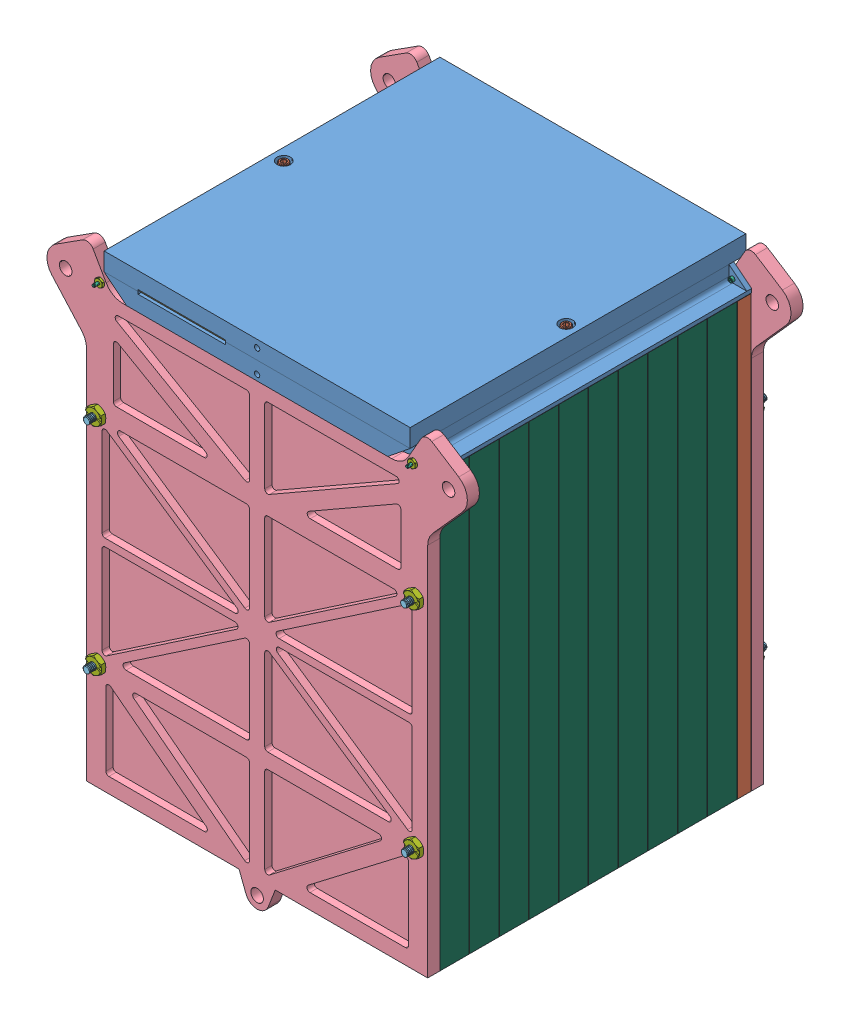
SolidWorks assembly Odd Stack, configuration Default. Lengths in mm.
Overall size (221.56 260.06 190.32).
276 component instances, 25 part files, 68 mates.
Components (placement in the parent):
- Tab Cover Odd-1: Tab Cover Odd [Default] at (178.2276 374.9734 440.7795) x (-1 0 0) z (0 -1 0) size (180.05 176.89 19.05)
- Socket 4-40 0.625in-1: Socket 4-40 0.625in [91251A112] at (252.6326 365.6234 440.7795) x (1 0 0) z (0 -1 0) size (4.65 4.65 19.13)
- Socket 4-40 0.625in-2: Socket 4-40 0.625in [91251A112] at (103.8226 365.6234 440.7795) x (1 0 0) z (0 -1 0) size (4.65 4.65 19.13)
- Steel Hex 4-40 Grade 2-1: Steel Hex 4-40 Grade 2 [90480A005] at (252.6326 367.2577 440.7795) size (6.35 2.87 7.33)
- Steel Hex 4-40 Grade 2-2: Steel Hex 4-40 Grade 2 [90480A005] at (103.8226 367.2577 440.7795) size (6.35 2.87 7.33)
- Two Cell Module-1: Two Cell Module [Default] at (101.24 129.6114 180.5218) size (179.74 245.1 23.68)
  - Cell Tab Config A-1: Cell Tab Config A [Default<As Machined>] at (76.9877 122.2307 189.17) size (160.6 237.16 14.27)
  - Cell Tab Config B-1: Cell Tab Config B [Default<As Machined>] at (76.9877 122.2307 197.4606) x (-1 0 0) z (0 0 -1) size (160.6 237.16 14.66)
  - Tab Load Spreader-1: Tab Load Spreader [Default] at (116.6877 245.8907 191.0069) x (-1 0 0) z (0 1 0) size (56.96 6.41 2.54)
  - Tab Load Spreader-2: Tab Load Spreader [Default] at (37.2877 245.8907 183.3655) x (-1 0 0) z (0 1 0) size (56.96 6.41 2.54)
  - Tab Load Spreader-3: Tab Load Spreader [Default] at (116.6877 242.8507 191.0069) x (-1 0 0) z (0 1 0) size (56.96 6.41 2.54)
  - Tab Load Spreader-4: Tab Load Spreader [Default] at (37.2877 242.8507 183.3655) x (-1 0 0) z (0 1 0) size (56.96 6.41 2.54)
  - Steel Toplock 6-32 Grade 2-1: Steel Toplock 6-32 Grade 2 [91837A008] at (141.9657 242.8507 191.0069) x (1 0 0) z (0 -1 0) size (7.94 9.17 3.14)
  - Steel 6-32 0.4375in-1: Steel 6-32 0.4375in [91251A178] at (141.9657 237.3182 191.0069) x (1 0 0) z (0 -1 0) size (5.74 5.74 15.07)
  - Steel Toplock 6-32 Grade 2-2: Steel Toplock 6-32 Grade 2 [91837A008] at (91.4097 242.8507 191.0069) x (1 0 0) z (0 -1 0) size (7.94 9.17 3.14)
  - Steel Toplock 6-32 Grade 2-3: Steel Toplock 6-32 Grade 2 [91837A008] at (62.5657 242.8507 183.3655) x (1 0 0) z (0 -1 0) size (7.94 9.17 3.14)
  - Steel Toplock 6-32 Grade 2-4: Steel Toplock 6-32 Grade 2 [91837A008] at (12.0097 242.8507 183.3655) x (1 0 0) z (0 -1 0) size (7.94 9.17 3.14)
  - Steel 6-32 0.4375in-2: Steel 6-32 0.4375in [91251A178] at (91.4097 237.3182 191.0069) x (1 0 0) z (0 -1 0) size (5.74 5.74 15.07)
  - Steel 6-32 0.4375in-3: Steel 6-32 0.4375in [91251A178] at (62.5657 237.3182 183.3655) x (1 0 0) z (0 -1 0) size (5.74 5.74 15.07)
  - Steel 6-32 0.4375in-4: Steel 6-32 0.4375in [91251A178] at (12.0097 237.3182 183.3655) x (1 0 0) z (0 -1 0) size (5.74 5.74 15.07)
  - Cell Board Middle-1: Cell Board Middle [Default] at (76.9877 244.9032 188.87) x (-1 0 0) z (0 0 1) size (20.32 17.15 2.64)
  - Cell Board Middle-2: Cell Board Middle [Default] at (76.9877 244.9032 197.1606) size (20.32 17.15 2.64)
  - Repeating Frame Outer-1: Repeating Frame Outer [Default] at (76.9877 115.9807 198.7766) size (179.3 226.63 1.59)
  - Repeating Frame Outer-2: Repeating Frame Outer [Default] at (76.9877 115.9807 186.2665) size (179.3 226.63 1.59)
  - Repeating Frame Inner-1: Repeating Frame Inner [Default] at (76.9877 116.0307 190.8106) size (179.3 226.73 6.35)
  - Insulation Film Back-1: Insulation Film Back [Default] at (76.9877 122.0246 185.62) x (-1 0 0) z (0 0 -1) size (179.74 227.29 0.36)
  - Insulation Film Full-1: Insulation Film Full [Default] at (76.9876 122.0664 201.0792) x (-1 0 0) z (0 0 -1) size (179.74 227.22 15.52)
  - Cell Load Spreader-1: Cell Load Spreader [Default] at (76.9877 115.9807 192.72) size (154 205.5 1.19)
  - Heat Sink Full-1: Heat Sink Full [Default] at (76.9877 122.0321 201.2316) x (-1 0 0) z (0 0 -1) size (179.74 227.15 15.45)
- Positive End Module-1: Positive End Module [Default] at (225.9096 129.8563 535.5842) x (-1 0 0) z (0 0 -1) size (179.74 245.1 14.97)
  - Cell Tab Config B Positive End-1: Cell Tab Config B Positive End [Default<As Machined>] at (47.682 121.9858 173.2819) size (160.6 236.86 14.97)
  - Repeating Frame Outer-1: Repeating Frame Outer [Default] at (47.682 115.7358 173.5819) size (179.3 226.63 1.59)
  - Repeating Frame Outer-2: Repeating Frame Outer [Default] at (47.682 115.7358 175.1694) size (179.3 226.63 1.59)
  - Repeating Frame Outer-3: Repeating Frame Outer [Default] at (47.682 115.7358 170.3784) size (179.3 226.63 1.59)
  - Cell Board End-1: Cell Board End [Default] at (47.682 240.5308 169.1719) x (-1 0 0) z (0 0 1) size (20.32 25.4 3.91)
  - Insulation Film Half-1: Insulation Film Half [Default] at (47.682 121.8215 169.6633) size (179.74 227.22 7.27)
  - Insulation Film End-1: Insulation Film End [Default] at (47.682 115.7358 176.8319) size (154 205.5 0.07)
  - Heat Sink Half-1: Heat Sink Half [Default] at (47.682 121.7872 169.5109) size (179.74 227.15 7.2)
- Negative End Module Odd-1: Negative End Module Odd [Default] at (101.24 129.6115 321.6437) size (179.74 245.1 28.8)
  - Cell Tab Config A-1: Cell Tab Config A [Default<As Machined>] at (76.9877 122.2307 189.17) size (160.6 237.16 14.27)
  - Cell Tab Config B Negative End-1: Cell Tab Config B Negative End [Default<As Machined>] at (76.9877 122.2307 197.4606) x (-1 0 0) z (0 0 -1) size (160.6 237.16 19.78)
  - Tab Load Spreader-1: Tab Load Spreader [Default] at (116.6877 245.8907 191.0069) x (-1 0 0) z (0 1 0) size (56.96 6.41 2.54)
  - Tab Load Spreader-2: Tab Load Spreader [Default] at (37.2877 245.8907 183.3655) x (-1 0 0) z (0 1 0) size (56.96 6.41 2.54)
  - Tab Load Spreader-3: Tab Load Spreader [Default] at (116.6877 242.8507 191.0069) x (-1 0 0) z (0 1 0) size (56.96 6.41 2.54)
  - Tab Load Spreader-4: Tab Load Spreader [Default] at (37.2877 242.8507 183.3655) x (-1 0 0) z (0 1 0) size (56.96 6.41 2.54)
  - Steel Toplock 6-32 Grade 2-1: Steel Toplock 6-32 Grade 2 [91837A008] at (141.9657 242.8507 191.0069) x (1 0 0) z (0 -1 0) size (7.94 9.17 3.14)
  - Steel Toplock 6-32 Grade 2-2: Steel Toplock 6-32 Grade 2 [91837A008] at (91.4097 242.8507 191.0069) x (1 0 0) z (0 -1 0) size (7.94 9.17 3.14)
  - Steel Toplock 6-32 Grade 2-3: Steel Toplock 6-32 Grade 2 [91837A008] at (62.5657 242.8507 183.3655) x (1 0 0) z (0 -1 0) size (7.94 9.17 3.14)
  - Steel Toplock 6-32 Grade 2-4: Steel Toplock 6-32 Grade 2 [91837A008] at (12.0097 242.8507 183.3655) x (1 0 0) z (0 -1 0) size (7.94 9.17 3.14)
  - Steel 6-32 0.4375in-1: Steel 6-32 0.4375in [91251A178] at (141.9657 237.3182 191.0069) x (1 0 0) z (0 -1 0) size (5.74 5.74 15.07)
  - Steel 6-32 0.4375in-2: Steel 6-32 0.4375in [91251A178] at (91.4097 237.3182 191.0069) x (1 0 0) z (0 -1 0) size (5.74 5.74 15.07)
  - Steel 6-32 0.4375in-3: Steel 6-32 0.4375in [91251A178] at (62.5657 237.3182 183.3655) x (1 0 0) z (0 -1 0) size (5.74 5.74 15.07)
  - Steel 6-32 0.4375in-4: Steel 6-32 0.4375in [91251A178] at (12.0097 237.3182 183.3655) x (1 0 0) z (0 -1 0) size (5.74 5.74 15.07)
  - Repeating Frame Outer-1: Repeating Frame Outer [Default] at (76.9877 115.9807 186.2665) size (179.3 226.63 1.59)
  - Repeating Frame Inner-1: Repeating Frame Inner [Default] at (76.9877 116.0307 190.8106) size (179.3 226.73 6.35)
  - Repeating Frame Outer-2: Repeating Frame Outer [Default] at (76.9877 115.9807 198.7766) size (179.3 226.63 1.59)
  - Cell Board Middle-1: Cell Board Middle [Default] at (76.9877 244.9032 188.87) x (-1 0 0) z (0 0 1) size (20.32 17.15 2.64)
  - Cell Board End-1: Cell Board End [Default] at (76.9877 240.7757 197.1606) x (1 0 0) z (0 0 -1) size (20.32 25.4 3.91)
  - Insulation Film Back-1: Insulation Film Back [Default] at (76.9877 122.0245 185.62) x (-1 0 0) z (0 0 -1) size (179.74 227.29 0.36)
  - Insulation Film Full-1: Insulation Film Full [Default] at (76.9876 122.0664 201.0792) x (-1 0 0) z (0 0 -1) size (179.74 227.22 15.52)
  - Cell Load Spreader-1: Cell Load Spreader [Default] at (76.9877 115.9807 192.72) size (154 205.5 1.19)
  - Heat Sink Full-1: Heat Sink Full [Default] at (76.9877 122.0321 201.2316) x (-1 0 0) z (0 0 -1) size (179.74 227.15 15.45)
- Two Cell Module-2: Two Cell Module [Default] at (101.24 129.6114 196.202) size (179.74 245.1 23.68)
  - Cell Tab Config A-1: Cell Tab Config A [Default<As Machined>] at (76.9877 122.2307 189.17) size (160.6 237.16 14.27)
  - Cell Tab Config B-1: Cell Tab Config B [Default<As Machined>] at (76.9877 122.2307 197.4606) x (-1 0 0) z (0 0 -1) size (160.6 237.16 14.66)
  - Tab Load Spreader-1: Tab Load Spreader [Default] at (116.6877 245.8907 191.0069) x (-1 0 0) z (0 1 0) size (56.96 6.41 2.54)
  - Tab Load Spreader-2: Tab Load Spreader [Default] at (37.2877 245.8907 183.3655) x (-1 0 0) z (0 1 0) size (56.96 6.41 2.54)
  - Tab Load Spreader-3: Tab Load Spreader [Default] at (116.6877 242.8507 191.0069) x (-1 0 0) z (0 1 0) size (56.96 6.41 2.54)
  - Tab Load Spreader-4: Tab Load Spreader [Default] at (37.2877 242.8507 183.3655) x (-1 0 0) z (0 1 0) size (56.96 6.41 2.54)
  - Steel Toplock 6-32 Grade 2-1: Steel Toplock 6-32 Grade 2 [91837A008] at (141.9657 242.8507 191.0069) x (1 0 0) z (0 -1 0) size (7.94 9.17 3.14)
  - Steel 6-32 0.4375in-1: Steel 6-32 0.4375in [91251A178] at (141.9657 237.3182 191.0069) x (1 0 0) z (0 -1 0) size (5.74 5.74 15.07)
  - Steel Toplock 6-32 Grade 2-2: Steel Toplock 6-32 Grade 2 [91837A008] at (91.4097 242.8507 191.0069) x (1 0 0) z (0 -1 0) size (7.94 9.17 3.14)
  - Steel Toplock 6-32 Grade 2-3: Steel Toplock 6-32 Grade 2 [91837A008] at (62.5657 242.8507 183.3655) x (1 0 0) z (0 -1 0) size (7.94 9.17 3.14)
  - Steel Toplock 6-32 Grade 2-4: Steel Toplock 6-32 Grade 2 [91837A008] at (12.0097 242.8507 183.3655) x (1 0 0) z (0 -1 0) size (7.94 9.17 3.14)
  - Steel 6-32 0.4375in-2: Steel 6-32 0.4375in [91251A178] at (91.4097 237.3182 191.0069) x (1 0 0) z (0 -1 0) size (5.74 5.74 15.07)
  - Steel 6-32 0.4375in-3: Steel 6-32 0.4375in [91251A178] at (62.5657 237.3182 183.3655) x (1 0 0) z (0 -1 0) size (5.74 5.74 15.07)
  - Steel 6-32 0.4375in-4: Steel 6-32 0.4375in [91251A178] at (12.0097 237.3182 183.3655) x (1 0 0) z (0 -1 0) size (5.74 5.74 15.07)
  - Cell Board Middle-1: Cell Board Middle [Default] at (76.9877 244.9032 188.87) x (-1 0 0) z (0 0 1) size (20.32 17.15 2.64)
  - Cell Board Middle-2: Cell Board Middle [Default] at (76.9877 244.9032 197.1606) size (20.32 17.15 2.64)
  - Repeating Frame Outer-1: Repeating Frame Outer [Default] at (76.9877 115.9807 198.7766) size (179.3 226.63 1.59)
  - Repeating Frame Outer-2: Repeating Frame Outer [Default] at (76.9877 115.9807 186.2665) size (179.3 226.63 1.59)
  - Repeating Frame Inner-1: Repeating Frame Inner [Default] at (76.9877 116.0307 190.8106) size (179.3 226.73 6.35)
  - Insulation Film Back-1: Insulation Film Back [Default] at (76.9877 122.0246 185.62) x (-1 0 0) z (0 0 -1) size (179.74 227.29 0.36)
  - Insulation Film Full-1: Insulation Film Full [Default] at (76.9876 122.0664 201.0792) x (-1 0 0) z (0 0 -1) size (179.74 227.22 15.52)
  - Cell Load Spreader-1: Cell Load Spreader [Default] at (76.9877 115.9807 192.72) size (154 205.5 1.19)
  - Heat Sink Full-1: Heat Sink Full [Default] at (76.9877 122.0321 201.2316) x (-1 0 0) z (0 0 -1) size (179.74 227.15 15.45)
- Two Cell Module-3: Two Cell Module [Default] at (101.24 129.6114 211.8822) size (179.74 245.1 23.68)
  - Cell Tab Config A-1: Cell Tab Config A [Default<As Machined>] at (76.9877 122.2307 189.17) size (160.6 237.16 14.27)
  - Cell Tab Config B-1: Cell Tab Config B [Default<As Machined>] at (76.9877 122.2307 197.4606) x (-1 0 0) z (0 0 -1) size (160.6 237.16 14.66)
  - Tab Load Spreader-1: Tab Load Spreader [Default] at (116.6877 245.8907 191.0069) x (-1 0 0) z (0 1 0) size (56.96 6.41 2.54)
  - Tab Load Spreader-2: Tab Load Spreader [Default] at (37.2877 245.8907 183.3655) x (-1 0 0) z (0 1 0) size (56.96 6.41 2.54)
  - Tab Load Spreader-3: Tab Load Spreader [Default] at (116.6877 242.8507 191.0069) x (-1 0 0) z (0 1 0) size (56.96 6.41 2.54)
  - Tab Load Spreader-4: Tab Load Spreader [Default] at (37.2877 242.8507 183.3655) x (-1 0 0) z (0 1 0) size (56.96 6.41 2.54)
  - Steel Toplock 6-32 Grade 2-1: Steel Toplock 6-32 Grade 2 [91837A008] at (141.9657 242.8507 191.0069) x (1 0 0) z (0 -1 0) size (7.94 9.17 3.14)
  - Steel 6-32 0.4375in-1: Steel 6-32 0.4375in [91251A178] at (141.9657 237.3182 191.0069) x (1 0 0) z (0 -1 0) size (5.74 5.74 15.07)
  - Steel Toplock 6-32 Grade 2-2: Steel Toplock 6-32 Grade 2 [91837A008] at (91.4097 242.8507 191.0069) x (1 0 0) z (0 -1 0) size (7.94 9.17 3.14)
  - Steel Toplock 6-32 Grade 2-3: Steel Toplock 6-32 Grade 2 [91837A008] at (62.5657 242.8507 183.3655) x (1 0 0) z (0 -1 0) size (7.94 9.17 3.14)
  - Steel Toplock 6-32 Grade 2-4: Steel Toplock 6-32 Grade 2 [91837A008] at (12.0097 242.8507 183.3655) x (1 0 0) z (0 -1 0) size (7.94 9.17 3.14)
  - Steel 6-32 0.4375in-2: Steel 6-32 0.4375in [91251A178] at (91.4097 237.3182 191.0069) x (1 0 0) z (0 -1 0) size (5.74 5.74 15.07)
  - Steel 6-32 0.4375in-3: Steel 6-32 0.4375in [91251A178] at (62.5657 237.3182 183.3655) x (1 0 0) z (0 -1 0) size (5.74 5.74 15.07)
  - Steel 6-32 0.4375in-4: Steel 6-32 0.4375in [91251A178] at (12.0097 237.3182 183.3655) x (1 0 0) z (0 -1 0) size (5.74 5.74 15.07)
  - Cell Board Middle-1: Cell Board Middle [Default] at (76.9877 244.9032 188.87) x (-1 0 0) z (0 0 1) size (20.32 17.15 2.64)
  - Cell Board Middle-2: Cell Board Middle [Default] at (76.9877 244.9032 197.1606) size (20.32 17.15 2.64)
  - Repeating Frame Outer-1: Repeating Frame Outer [Default] at (76.9877 115.9807 198.7766) size (179.3 226.63 1.59)
  - Repeating Frame Outer-2: Repeating Frame Outer [Default] at (76.9877 115.9807 186.2665) size (179.3 226.63 1.59)
  - Repeating Frame Inner-1: Repeating Frame Inner [Default] at (76.9877 116.0307 190.8106) size (179.3 226.73 6.35)
  - Insulation Film Back-1: Insulation Film Back [Default] at (76.9877 122.0246 185.62) x (-1 0 0) z (0 0 -1) size (179.74 227.29 0.36)
  - Insulation Film Full-1: Insulation Film Full [Default] at (76.9876 122.0664 201.0792) x (-1 0 0) z (0 0 -1) size (179.74 227.22 15.52)
  - Cell Load Spreader-1: Cell Load Spreader [Default] at (76.9877 115.9807 192.72) size (154 205.5 1.19)
  - Heat Sink Full-1: Heat Sink Full [Default] at (76.9877 122.0321 201.2316) x (-1 0 0) z (0 0 -1) size (179.74 227.15 15.45)
- Two Cell Module-4: Two Cell Module [Default] at (101.24 129.6114 227.5624) size (179.74 245.1 23.68)
  - Cell Tab Config A-1: Cell Tab Config A [Default<As Machined>] at (76.9877 122.2307 189.17) size (160.6 237.16 14.27)
  - Cell Tab Config B-1: Cell Tab Config B [Default<As Machined>] at (76.9877 122.2307 197.4606) x (-1 0 0) z (0 0 -1) size (160.6 237.16 14.66)
  - Tab Load Spreader-1: Tab Load Spreader [Default] at (116.6877 245.8907 191.0069) x (-1 0 0) z (0 1 0) size (56.96 6.41 2.54)
  - Tab Load Spreader-2: Tab Load Spreader [Default] at (37.2877 245.8907 183.3655) x (-1 0 0) z (0 1 0) size (56.96 6.41 2.54)
  - Tab Load Spreader-3: Tab Load Spreader [Default] at (116.6877 242.8507 191.0069) x (-1 0 0) z (0 1 0) size (56.96 6.41 2.54)
  - Tab Load Spreader-4: Tab Load Spreader [Default] at (37.2877 242.8507 183.3655) x (-1 0 0) z (0 1 0) size (56.96 6.41 2.54)
  - Steel Toplock 6-32 Grade 2-1: Steel Toplock 6-32 Grade 2 [91837A008] at (141.9657 242.8507 191.0069) x (1 0 0) z (0 -1 0) size (7.94 9.17 3.14)
  - Steel 6-32 0.4375in-1: Steel 6-32 0.4375in [91251A178] at (141.9657 237.3182 191.0069) x (1 0 0) z (0 -1 0) size (5.74 5.74 15.07)
  - Steel Toplock 6-32 Grade 2-2: Steel Toplock 6-32 Grade 2 [91837A008] at (91.4097 242.8507 191.0069) x (1 0 0) z (0 -1 0) size (7.94 9.17 3.14)
  - Steel Toplock 6-32 Grade 2-3: Steel Toplock 6-32 Grade 2 [91837A008] at (62.5657 242.8507 183.3655) x (1 0 0) z (0 -1 0) size (7.94 9.17 3.14)
  - Steel Toplock 6-32 Grade 2-4: Steel Toplock 6-32 Grade 2 [91837A008] at (12.0097 242.8507 183.3655) x (1 0 0) z (0 -1 0) size (7.94 9.17 3.14)
  - Steel 6-32 0.4375in-2: Steel 6-32 0.4375in [91251A178] at (91.4097 237.3182 191.0069) x (1 0 0) z (0 -1 0) size (5.74 5.74 15.07)
  - Steel 6-32 0.4375in-3: Steel 6-32 0.4375in [91251A178] at (62.5657 237.3182 183.3655) x (1 0 0) z (0 -1 0) size (5.74 5.74 15.07)
  - Steel 6-32 0.4375in-4: Steel 6-32 0.4375in [91251A178] at (12.0097 237.3182 183.3655) x (1 0 0) z (0 -1 0) size (5.74 5.74 15.07)
  - Cell Board Middle-1: Cell Board Middle [Default] at (76.9877 244.9032 188.87) x (-1 0 0) z (0 0 1) size (20.32 17.15 2.64)
  - Cell Board Middle-2: Cell Board Middle [Default] at (76.9877 244.9032 197.1606) size (20.32 17.15 2.64)
  - Repeating Frame Outer-1: Repeating Frame Outer [Default] at (76.9877 115.9807 198.7766) size (179.3 226.63 1.59)
  - Repeating Frame Outer-2: Repeating Frame Outer [Default] at (76.9877 115.9807 186.2665) size (179.3 226.63 1.59)
  - Repeating Frame Inner-1: Repeating Frame Inner [Default] at (76.9877 116.0307 190.8106) size (179.3 226.73 6.35)
  - Insulation Film Back-1: Insulation Film Back [Default] at (76.9877 122.0246 185.62) x (-1 0 0) z (0 0 -1) size (179.74 227.29 0.36)
  - Insulation Film Full-1: Insulation Film Full [Default] at (76.9876 122.0664 201.0792) x (-1 0 0) z (0 0 -1) size (179.74 227.22 15.52)
  - Cell Load Spreader-1: Cell Load Spreader [Default] at (76.9877 115.9807 192.72) size (154 205.5 1.19)
  - Heat Sink Full-1: Heat Sink Full [Default] at (76.9877 122.0321 201.2316) x (-1 0 0) z (0 0 -1) size (179.74 227.15 15.45)
- Two Cell Module-5: Two Cell Module [Default] at (101.24 129.6114 243.2426) size (179.74 245.1 23.68)
  - Cell Tab Config A-1: Cell Tab Config A [Default<As Machined>] at (76.9877 122.2307 189.17) size (160.6 237.16 14.27)
  - Cell Tab Config B-1: Cell Tab Config B [Default<As Machined>] at (76.9877 122.2307 197.4606) x (-1 0 0) z (0 0 -1) size (160.6 237.16 14.66)
  - Tab Load Spreader-1: Tab Load Spreader [Default] at (116.6877 245.8907 191.0069) x (-1 0 0) z (0 1 0) size (56.96 6.41 2.54)
  - Tab Load Spreader-2: Tab Load Spreader [Default] at (37.2877 245.8907 183.3655) x (-1 0 0) z (0 1 0) size (56.96 6.41 2.54)
  - Tab Load Spreader-3: Tab Load Spreader [Default] at (116.6877 242.8507 191.0069) x (-1 0 0) z (0 1 0) size (56.96 6.41 2.54)
  - Tab Load Spreader-4: Tab Load Spreader [Default] at (37.2877 242.8507 183.3655) x (-1 0 0) z (0 1 0) size (56.96 6.41 2.54)
  - Steel Toplock 6-32 Grade 2-1: Steel Toplock 6-32 Grade 2 [91837A008] at (141.9657 242.8507 191.0069) x (1 0 0) z (0 -1 0) size (7.94 9.17 3.14)
  - Steel 6-32 0.4375in-1: Steel 6-32 0.4375in [91251A178] at (141.9657 237.3182 191.0069) x (1 0 0) z (0 -1 0) size (5.74 5.74 15.07)
  - Steel Toplock 6-32 Grade 2-2: Steel Toplock 6-32 Grade 2 [91837A008] at (91.4097 242.8507 191.0069) x (1 0 0) z (0 -1 0) size (7.94 9.17 3.14)
  - Steel Toplock 6-32 Grade 2-3: Steel Toplock 6-32 Grade 2 [91837A008] at (62.5657 242.8507 183.3655) x (1 0 0) z (0 -1 0) size (7.94 9.17 3.14)
  - Steel Toplock 6-32 Grade 2-4: Steel Toplock 6-32 Grade 2 [91837A008] at (12.0097 242.8507 183.3655) x (1 0 0) z (0 -1 0) size (7.94 9.17 3.14)
  - Steel 6-32 0.4375in-2: Steel 6-32 0.4375in [91251A178] at (91.4097 237.3182 191.0069) x (1 0 0) z (0 -1 0) size (5.74 5.74 15.07)
  - Steel 6-32 0.4375in-3: Steel 6-32 0.4375in [91251A178] at (62.5657 237.3182 183.3655) x (1 0 0) z (0 -1 0) size (5.74 5.74 15.07)
  - Steel 6-32 0.4375in-4: Steel 6-32 0.4375in [91251A178] at (12.0097 237.3182 183.3655) x (1 0 0) z (0 -1 0) size (5.74 5.74 15.07)
  - Cell Board Middle-1: Cell Board Middle [Default] at (76.9877 244.9032 188.87) x (-1 0 0) z (0 0 1) size (20.32 17.15 2.64)
  - Cell Board Middle-2: Cell Board Middle [Default] at (76.9877 244.9032 197.1606) size (20.32 17.15 2.64)
  - Repeating Frame Outer-1: Repeating Frame Outer [Default] at (76.9877 115.9807 198.7766) size (179.3 226.63 1.59)
  - Repeating Frame Outer-2: Repeating Frame Outer [Default] at (76.9877 115.9807 186.2665) size (179.3 226.63 1.59)
  - Repeating Frame Inner-1: Repeating Frame Inner [Default] at (76.9877 116.0307 190.8106) size (179.3 226.73 6.35)
  - Insulation Film Back-1: Insulation Film Back [Default] at (76.9877 122.0246 185.62) x (-1 0 0) z (0 0 -1) size (179.74 227.29 0.36)
  - Insulation Film Full-1: Insulation Film Full [Default] at (76.9876 122.0664 201.0792) x (-1 0 0) z (0 0 -1) size (179.74 227.22 15.52)
  - Cell Load Spreader-1: Cell Load Spreader [Default] at (76.9877 115.9807 192.72) size (154 205.5 1.19)
  - Heat Sink Full-1: Heat Sink Full [Default] at (76.9877 122.0321 201.2316) x (-1 0 0) z (0 0 -1) size (179.74 227.15 15.45)
- Two Cell Module-6: Two Cell Module [Default] at (101.24 129.6114 258.9228) size (179.74 245.1 23.68)
  - Cell Tab Config A-1: Cell Tab Config A [Default<As Machined>] at (76.9877 122.2307 189.17) size (160.6 237.16 14.27)
  - Cell Tab Config B-1: Cell Tab Config B [Default<As Machined>] at (76.9877 122.2307 197.4606) x (-1 0 0) z (0 0 -1) size (160.6 237.16 14.66)
  - Tab Load Spreader-1: Tab Load Spreader [Default] at (116.6877 245.8907 191.0069) x (-1 0 0) z (0 1 0) size (56.96 6.41 2.54)
  - Tab Load Spreader-2: Tab Load Spreader [Default] at (37.2877 245.8907 183.3655) x (-1 0 0) z (0 1 0) size (56.96 6.41 2.54)
  - Tab Load Spreader-3: Tab Load Spreader [Default] at (116.6877 242.8507 191.0069) x (-1 0 0) z (0 1 0) size (56.96 6.41 2.54)
  - Tab Load Spreader-4: Tab Load Spreader [Default] at (37.2877 242.8507 183.3655) x (-1 0 0) z (0 1 0) size (56.96 6.41 2.54)
  - Steel Toplock 6-32 Grade 2-1: Steel Toplock 6-32 Grade 2 [91837A008] at (141.9657 242.8507 191.0069) x (1 0 0) z (0 -1 0) size (7.94 9.17 3.14)
  - Steel 6-32 0.4375in-1: Steel 6-32 0.4375in [91251A178] at (141.9657 237.3182 191.0069) x (1 0 0) z (0 -1 0) size (5.74 5.74 15.07)
  - Steel Toplock 6-32 Grade 2-2: Steel Toplock 6-32 Grade 2 [91837A008] at (91.4097 242.8507 191.0069) x (1 0 0) z (0 -1 0) size (7.94 9.17 3.14)
  - Steel Toplock 6-32 Grade 2-3: Steel Toplock 6-32 Grade 2 [91837A008] at (62.5657 242.8507 183.3655) x (1 0 0) z (0 -1 0) size (7.94 9.17 3.14)
  - Steel Toplock 6-32 Grade 2-4: Steel Toplock 6-32 Grade 2 [91837A008] at (12.0097 242.8507 183.3655) x (1 0 0) z (0 -1 0) size (7.94 9.17 3.14)
  - Steel 6-32 0.4375in-2: Steel 6-32 0.4375in [91251A178] at (91.4097 237.3182 191.0069) x (1 0 0) z (0 -1 0) size (5.74 5.74 15.07)
  - Steel 6-32 0.4375in-3: Steel 6-32 0.4375in [91251A178] at (62.5657 237.3182 183.3655) x (1 0 0) z (0 -1 0) size (5.74 5.74 15.07)
  - Steel 6-32 0.4375in-4: Steel 6-32 0.4375in [91251A178] at (12.0097 237.3182 183.3655) x (1 0 0) z (0 -1 0) size (5.74 5.74 15.07)
  - Cell Board Middle-1: Cell Board Middle [Default] at (76.9877 244.9032 188.87) x (-1 0 0) z (0 0 1) size (20.32 17.15 2.64)
  - Cell Board Middle-2: Cell Board Middle [Default] at (76.9877 244.9032 197.1606) size (20.32 17.15 2.64)
  - Repeating Frame Outer-1: Repeating Frame Outer [Default] at (76.9877 115.9807 198.7766) size (179.3 226.63 1.59)
  - Repeating Frame Outer-2: Repeating Frame Outer [Default] at (76.9877 115.9807 186.2665) size (179.3 226.63 1.59)
  - Repeating Frame Inner-1: Repeating Frame Inner [Default] at (76.9877 116.0307 190.8106) size (179.3 226.73 6.35)
  - Insulation Film Back-1: Insulation Film Back [Default] at (76.9877 122.0246 185.62) x (-1 0 0) z (0 0 -1) size (179.74 227.29 0.36)
  - Insulation Film Full-1: Insulation Film Full [Default] at (76.9876 122.0664 201.0792) x (-1 0 0) z (0 0 -1) size (179.74 227.22 15.52)
  - Cell Load Spreader-1: Cell Load Spreader [Default] at (76.9877 115.9807 192.72) size (154 205.5 1.19)
  - Heat Sink Full-1: Heat Sink Full [Default] at (76.9877 122.0321 201.2316) x (-1 0 0) z (0 0 -1) size (179.74 227.15 15.45)
- Two Cell Module-7: Two Cell Module [Default] at (101.24 129.6114 274.603) size (179.74 245.1 23.68)
  - Cell Tab Config A-1: Cell Tab Config A [Default<As Machined>] at (76.9877 122.2307 189.17) size (160.6 237.16 14.27)
  - Cell Tab Config B-1: Cell Tab Config B [Default<As Machined>] at (76.9877 122.2307 197.4606) x (-1 0 0) z (0 0 -1) size (160.6 237.16 14.66)
  - Tab Load Spreader-1: Tab Load Spreader [Default] at (116.6877 245.8907 191.0069) x (-1 0 0) z (0 1 0) size (56.96 6.41 2.54)
  - Tab Load Spreader-2: Tab Load Spreader [Default] at (37.2877 245.8907 183.3655) x (-1 0 0) z (0 1 0) size (56.96 6.41 2.54)
  - Tab Load Spreader-3: Tab Load Spreader [Default] at (116.6877 242.8507 191.0069) x (-1 0 0) z (0 1 0) size (56.96 6.41 2.54)
  - Tab Load Spreader-4: Tab Load Spreader [Default] at (37.2877 242.8507 183.3655) x (-1 0 0) z (0 1 0) size (56.96 6.41 2.54)
  - Steel Toplock 6-32 Grade 2-1: Steel Toplock 6-32 Grade 2 [91837A008] at (141.9657 242.8507 191.0069) x (1 0 0) z (0 -1 0) size (7.94 9.17 3.14)
  - Steel 6-32 0.4375in-1: Steel 6-32 0.4375in [91251A178] at (141.9657 237.3182 191.0069) x (1 0 0) z (0 -1 0) size (5.74 5.74 15.07)
  - Steel Toplock 6-32 Grade 2-2: Steel Toplock 6-32 Grade 2 [91837A008] at (91.4097 242.8507 191.0069) x (1 0 0) z (0 -1 0) size (7.94 9.17 3.14)
  - Steel Toplock 6-32 Grade 2-3: Steel Toplock 6-32 Grade 2 [91837A008] at (62.5657 242.8507 183.3655) x (1 0 0) z (0 -1 0) size (7.94 9.17 3.14)
  - Steel Toplock 6-32 Grade 2-4: Steel Toplock 6-32 Grade 2 [91837A008] at (12.0097 242.8507 183.3655) x (1 0 0) z (0 -1 0) size (7.94 9.17 3.14)
  - Steel 6-32 0.4375in-2: Steel 6-32 0.4375in [91251A178] at (91.4097 237.3182 191.0069) x (1 0 0) z (0 -1 0) size (5.74 5.74 15.07)
  - Steel 6-32 0.4375in-3: Steel 6-32 0.4375in [91251A178] at (62.5657 237.3182 183.3655) x (1 0 0) z (0 -1 0) size (5.74 5.74 15.07)
  - Steel 6-32 0.4375in-4: Steel 6-32 0.4375in [91251A178] at (12.0097 237.3182 183.3655) x (1 0 0) z (0 -1 0) size (5.74 5.74 15.07)
  - Cell Board Middle-1: Cell Board Middle [Default] at (76.9877 244.9032 188.87) x (-1 0 0) z (0 0 1) size (20.32 17.15 2.64)
  - Cell Board Middle-2: Cell Board Middle [Default] at (76.9877 244.9032 197.1606) size (20.32 17.15 2.64)
  - Repeating Frame Outer-1: Repeating Frame Outer [Default] at (76.9877 115.9807 198.7766) size (179.3 226.63 1.59)
  - Repeating Frame Outer-2: Repeating Frame Outer [Default] at (76.9877 115.9807 186.2665) size (179.3 226.63 1.59)
  - Repeating Frame Inner-1: Repeating Frame Inner [Default] at (76.9877 116.0307 190.8106) size (179.3 226.73 6.35)
  - Insulation Film Back-1: Insulation Film Back [Default] at (76.9877 122.0246 185.62) x (-1 0 0) z (0 0 -1) size (179.74 227.29 0.36)
  - Insulation Film Full-1: Insulation Film Full [Default] at (76.9876 122.0664 201.0792) x (-1 0 0) z (0 0 -1) size (179.74 227.22 15.52)
  - Cell Load Spreader-1: Cell Load Spreader [Default] at (76.9877 115.9807 192.72) size (154 205.5 1.19)
  - Heat Sink Full-1: Heat Sink Full [Default] at (76.9877 122.0321 201.2316) x (-1 0 0) z (0 0 -1) size (179.74 227.15 15.45)
- Two Cell Module-8: Two Cell Module [Default] at (101.24 129.6114 290.2832) size (179.74 245.1 23.68)
  - Cell Tab Config A-1: Cell Tab Config A [Default<As Machined>] at (76.9877 122.2307 189.17) size (160.6 237.16 14.27)
  - Cell Tab Config B-1: Cell Tab Config B [Default<As Machined>] at (76.9877 122.2307 197.4606) x (-1 0 0) z (0 0 -1) size (160.6 237.16 14.66)
  - Tab Load Spreader-1: Tab Load Spreader [Default] at (116.6877 245.8907 191.0069) x (-1 0 0) z (0 1 0) size (56.96 6.41 2.54)
  - Tab Load Spreader-2: Tab Load Spreader [Default] at (37.2877 245.8907 183.3655) x (-1 0 0) z (0 1 0) size (56.96 6.41 2.54)
  - Tab Load Spreader-3: Tab Load Spreader [Default] at (116.6877 242.8507 191.0069) x (-1 0 0) z (0 1 0) size (56.96 6.41 2.54)
  - Tab Load Spreader-4: Tab Load Spreader [Default] at (37.2877 242.8507 183.3655) x (-1 0 0) z (0 1 0) size (56.96 6.41 2.54)
  - Steel Toplock 6-32 Grade 2-1: Steel Toplock 6-32 Grade 2 [91837A008] at (141.9657 242.8507 191.0069) x (1 0 0) z (0 -1 0) size (7.94 9.17 3.14)
  - Steel 6-32 0.4375in-1: Steel 6-32 0.4375in [91251A178] at (141.9657 237.3182 191.0069) x (1 0 0) z (0 -1 0) size (5.74 5.74 15.07)
  - Steel Toplock 6-32 Grade 2-2: Steel Toplock 6-32 Grade 2 [91837A008] at (91.4097 242.8507 191.0069) x (1 0 0) z (0 -1 0) size (7.94 9.17 3.14)
  - Steel Toplock 6-32 Grade 2-3: Steel Toplock 6-32 Grade 2 [91837A008] at (62.5657 242.8507 183.3655) x (1 0 0) z (0 -1 0) size (7.94 9.17 3.14)
  - Steel Toplock 6-32 Grade 2-4: Steel Toplock 6-32 Grade 2 [91837A008] at (12.0097 242.8507 183.3655) x (1 0 0) z (0 -1 0) size (7.94 9.17 3.14)
  - Steel 6-32 0.4375in-2: Steel 6-32 0.4375in [91251A178] at (91.4097 237.3182 191.0069) x (1 0 0) z (0 -1 0) size (5.74 5.74 15.07)
  - Steel 6-32 0.4375in-3: Steel 6-32 0.4375in [91251A178] at (62.5657 237.3182 183.3655) x (1 0 0) z (0 -1 0) size (5.74 5.74 15.07)
  - Steel 6-32 0.4375in-4: Steel 6-32 0.4375in [91251A178] at (12.0097 237.3182 183.3655) x (1 0 0) z (0 -1 0) size (5.74 5.74 15.07)
  - Cell Board Middle-1: Cell Board Middle [Default] at (76.9877 244.9032 188.87) x (-1 0 0) z (0 0 1) size (20.32 17.15 2.64)
  - Cell Board Middle-2: Cell Board Middle [Default] at (76.9877 244.9032 197.1606) size (20.32 17.15 2.64)
  - Repeating Frame Outer-1: Repeating Frame Outer [Default] at (76.9877 115.9807 198.7766) size (179.3 226.63 1.59)
  - Repeating Frame Outer-2: Repeating Frame Outer [Default] at (76.9877 115.9807 186.2665) size (179.3 226.63 1.59)
  - Repeating Frame Inner-1: Repeating Frame Inner [Default] at (76.9877 116.0307 190.8106) size (179.3 226.73 6.35)
  - Insulation Film Back-1: Insulation Film Back [Default] at (76.9877 122.0246 185.62) x (-1 0 0) z (0 0 -1) size (179.74 227.29 0.36)
  - Insulation Film Full-1: Insulation Film Full [Default] at (76.9876 122.0664 201.0792) x (-1 0 0) z (0 0 -1) size (179.74 227.22 15.52)
  - Cell Load Spreader-1: Cell Load Spreader [Default] at (76.9877 115.9807 192.72) size (154 205.5 1.19)
  - Heat Sink Full-1: Heat Sink Full [Default] at (76.9877 122.0321 201.2316) x (-1 0 0) z (0 0 -1) size (179.74 227.15 15.45)
- Two Cell Module-9: Two Cell Module [Default] at (101.24 129.6114 305.9634) size (179.74 245.1 23.68)
  - Cell Tab Config A-1: Cell Tab Config A [Default<As Machined>] at (76.9877 122.2307 189.17) size (160.6 237.16 14.27)
  - Cell Tab Config B-1: Cell Tab Config B [Default<As Machined>] at (76.9877 122.2307 197.4606) x (-1 0 0) z (0 0 -1) size (160.6 237.16 14.66)
  - Tab Load Spreader-1: Tab Load Spreader [Default] at (116.6877 245.8907 191.0069) x (-1 0 0) z (0 1 0) size (56.96 6.41 2.54)
  - Tab Load Spreader-2: Tab Load Spreader [Default] at (37.2877 245.8907 183.3655) x (-1 0 0) z (0 1 0) size (56.96 6.41 2.54)
  - Tab Load Spreader-3: Tab Load Spreader [Default] at (116.6877 242.8507 191.0069) x (-1 0 0) z (0 1 0) size (56.96 6.41 2.54)
  - Tab Load Spreader-4: Tab Load Spreader [Default] at (37.2877 242.8507 183.3655) x (-1 0 0) z (0 1 0) size (56.96 6.41 2.54)
  - Steel Toplock 6-32 Grade 2-1: Steel Toplock 6-32 Grade 2 [91837A008] at (141.9657 242.8507 191.0069) x (1 0 0) z (0 -1 0) size (7.94 9.17 3.14)
  - Steel 6-32 0.4375in-1: Steel 6-32 0.4375in [91251A178] at (141.9657 237.3182 191.0069) x (1 0 0) z (0 -1 0) size (5.74 5.74 15.07)
  - Steel Toplock 6-32 Grade 2-2: Steel Toplock 6-32 Grade 2 [91837A008] at (91.4097 242.8507 191.0069) x (1 0 0) z (0 -1 0) size (7.94 9.17 3.14)
  - Steel Toplock 6-32 Grade 2-3: Steel Toplock 6-32 Grade 2 [91837A008] at (62.5657 242.8507 183.3655) x (1 0 0) z (0 -1 0) size (7.94 9.17 3.14)
  - Steel Toplock 6-32 Grade 2-4: Steel Toplock 6-32 Grade 2 [91837A008] at (12.0097 242.8507 183.3655) x (1 0 0) z (0 -1 0) size (7.94 9.17 3.14)
  - Steel 6-32 0.4375in-2: Steel 6-32 0.4375in [91251A178] at (91.4097 237.3182 191.0069) x (1 0 0) z (0 -1 0) size (5.74 5.74 15.07)
  - Steel 6-32 0.4375in-3: Steel 6-32 0.4375in [91251A178] at (62.5657 237.3182 183.3655) x (1 0 0) z (0 -1 0) size (5.74 5.74 15.07)
  - Steel 6-32 0.4375in-4: Steel 6-32 0.4375in [91251A178] at (12.0097 237.3182 183.3655) x (1 0 0) z (0 -1 0) size (5.74 5.74 15.07)
  - Cell Board Middle-1: Cell Board Middle [Default] at (76.9877 244.9032 188.87) x (-1 0 0) z (0 0 1) size (20.32 17.15 2.64)
  - Cell Board Middle-2: Cell Board Middle [Default] at (76.9877 244.9032 197.1606) size (20.32 17.15 2.64)
  - Repeating Frame Outer-1: Repeating Frame Outer [Default] at (76.9877 115.9807 198.7766) size (179.3 226.63 1.59)
  - Repeating Frame Outer-2: Repeating Frame Outer [Default] at (76.9877 115.9807 186.2665) size (179.3 226.63 1.59)
  - Repeating Frame Inner-1: Repeating Frame Inner [Default] at (76.9877 116.0307 190.8106) size (179.3 226.73 6.35)
  - Insulation Film Back-1: Insulation Film Back [Default] at (76.9877 122.0246 185.62) x (-1 0 0) z (0 0 -1) size (179.74 227.29 0.36)
  - Insulation Film Full-1: Insulation Film Full [Default] at (76.9876 122.0664 201.0792) x (-1 0 0) z (0 0 -1) size (179.74 227.22 15.52)
  - Cell Load Spreader-1: Cell Load Spreader [Default] at (76.9877 115.9807 192.72) size (154 205.5 1.19)
  - Heat Sink Full-1: Heat Sink Full [Default] at (76.9877 122.0321 201.2316) x (-1 0 0) z (0 0 -1) size (179.74 227.15 15.45)
- End Plate-1: End Plate [Default] at (178.2276 251.7197 358.6836) size (221.56 260.06 6.35)
- End Plate-2: End Plate [Default] at (178.2276 251.7198 522.8753) x (-1 0 0) z (0 0 -1) size (221.56 260.06 6.35)
- Odd Threaded Rod-1: Odd Threaded Rod [Default] at (94.5076 308.6221 345.9836) x (0.372192 -0.928156 0) z (0 0 1) size (3.68 3.53 190.32)
- Odd Threaded Rod-2: Odd Threaded Rod [Default] at (94.5076 194.9697 345.9836) x (-0.41615 -0.909296 0) z (0 0 1) size (3.68 3.53 190.32)
- Odd Threaded Rod-3: Odd Threaded Rod [Default] at (261.9476 308.6221 345.9836) x (-0.872978 0.487759 0) z (0 0 1) size (3.68 3.53 190.32)
- Odd Threaded Rod-4: Odd Threaded Rod [Default] at (261.9476 194.9697 345.9836) x (0.84239 -0.538868 0) z (0 0 1) size (3.68 3.53 190.32)
- Steel Toplock 6-32 Grade 2-1: Steel Toplock 6-32 Grade 2 [91837A008] at (261.9476 308.6222 529.2253) x (1 0.000127 0) z (0 0 1) size (7.94 9.17 3.14)
- Steel Toplock 6-32 Grade 2-2: Steel Toplock 6-32 Grade 2 [91837A008] at (261.9476 194.9698 529.2253) x (1 0.000127 0) z (0 0 1) size (7.94 9.17 3.14)
- Steel Toplock 6-32 Grade 2-3: Steel Toplock 6-32 Grade 2 [91837A008] at (94.5076 194.9698 529.2253) x (1 0.000127 0) z (0 0 1) size (7.94 9.17 3.14)
- Steel Toplock 6-32 Grade 2-4: Steel Toplock 6-32 Grade 2 [91837A008] at (94.5076 308.6222 529.2253) x (1 0.000127 0) z (0 0 1) size (7.94 9.17 3.14)
- Steel Toplock 6-32 Grade 2-5: Steel Toplock 6-32 Grade 2 [91837A008] at (261.9476 308.6221 352.3336) x (-1 -0.000127 0) z (0 0 -1) size (7.94 9.17 3.14)
- Steel Toplock 6-32 Grade 2-6: Steel Toplock 6-32 Grade 2 [91837A008] at (94.5076 308.6221 352.3336) x (-1 -0.000127 0) z (0 0 -1) size (7.94 9.17 3.14)
- Steel Toplock 6-32 Grade 2-7: Steel Toplock 6-32 Grade 2 [91837A008] at (94.5076 194.9697 352.3336) x (-1 -0.000127 0) z (0 0 -1) size (7.94 9.17 3.14)
- Steel Toplock 6-32 Grade 2-8: Steel Toplock 6-32 Grade 2 [91837A008] at (261.9476 194.9697 352.3336) x (-1 -0.000127 0) z (0 0 -1) size (7.94 9.17 3.14)
- Steel 0-80 1_2in-1: Steel 0-80 1_2in [91251A059] at (260.8326 369.4484 348.5237) x (-0.923728 -0.383049 0) z (0 0 -1) size (2.44 2.44 14.46)
- Steel 0-80 1_2in-2: Steel 0-80 1_2in [91251A059] at (95.6226 369.4484 348.5237) x (-0.923728 -0.383049 0) z (0 0 -1) size (2.44 2.44 14.46)
- Steel Hex 0-80 Grade 2-1: Steel Hex 0-80 Grade 2 [90480A001] at (260.6802 369.4483 351.7383) x (1 0 0) z (0 1 0) size (3.97 1.53 4.58)
- Steel Hex 0-80 Grade 2-2: Steel Hex 0-80 Grade 2 [90480A001] at (95.775 369.4483 351.7383) x (1 0 0) z (0 1 0) size (3.97 1.53 4.58)
- Steel 0-80 1_2in-3: Steel 0-80 1_2in [91251A059] at (95.6226 369.4484 533.0353) size (2.44 2.44 14.46)
- Steel Hex 0-80 Grade 2-3: Steel Hex 0-80 Grade 2 [90480A001] at (95.775 369.4484 529.8206) x (1 0 0) z (0 1 0) size (3.97 1.53 4.58)
- Steel Hex 0-80 Grade 2-4: Steel Hex 0-80 Grade 2 [90480A001] at (260.6802 369.4484 529.8206) x (1 0 0) z (0 -1 0) size (3.97 1.53 4.58)
- Steel 0-80 1_2in-4: Steel 0-80 1_2in [91251A059] at (260.8326 369.4484 533.0353) size (2.44 2.44 14.46)
Mates (geometry in assembly coordinates):
- Concentric2: concentric anti-aligned: circle of Odd Threaded Rod-4; circle of End Plate-1
- Concentric3: concentric anti-aligned: circle of Odd Threaded Rod-3; circle of End Plate-1
- Concentric4: concentric aligned: circle of Odd Threaded Rod-2; circle of End Plate-1
- Concentric5: concentric aligned: circle of Odd Threaded Rod-1; circle of End Plate-1
- Distance1: distance = 6.35 mm aligned: plane of Odd Threaded Rod-3 through (261.9476 308.6221 345.9836) normal (0 0 -1); plane of End Plate-1 through (178.2276 251.7197 352.3336) normal (0 0 -1)
- Distance2: distance = 6.35 mm aligned: plane of Odd Threaded Rod-2 through (94.5076 194.9697 345.9836) normal (0 0 -1); plane of End Plate-1 through (178.2276 251.7197 352.3336) normal (0 0 -1)
- Distance3: distance = 6.35 mm aligned: plane of Odd Threaded Rod-1 through (94.5076 308.6221 345.9836) normal (0 0 -1); plane of End Plate-1 through (178.2276 251.7197 352.3336) normal (0 0 -1)
- Distance4: distance = 6.35 mm aligned: plane of Odd Threaded Rod-4 through (261.9476 194.9697 345.9836) normal (0 0 -1); plane of End Plate-1 through (178.2276 251.7197 352.3336) normal (0 0 -1)
- Coincident56: coincident anti-aligned: plane of Tab Cover Odd-1; plane of End Plate-1 through (178.2276 251.7197 358.6836) normal (1 0 0)
- Concentric25: concentric aligned: circle of Two Cell Module-9/Heat Sink Full-1; circle of Negative End Module Odd-1/Insulation Film Back-1
- Coincident60: coincident aligned: circle of Two Cell Module-9/Heat Sink Full-1; circle of Negative End Module Odd-1/Insulation Film Back-1
- Concentric26: concentric aligned: circle of Two Cell Module-1/Insulation Film Back-1; circle of Positive End Module-1/Heat Sink Half-1
- Coincident62: coincident aligned: circle of Two Cell Module-1/Insulation Film Back-1; circle of Positive End Module-1/Heat Sink Half-1
- Coincident67: coincident anti-aligned: plane of Positive End Module-1/Insulation Film End-1 through (178.2276 245.5921 358.6836) normal (0 0 -1); plane of End Plate-1 through (178.2276 251.7197 358.6836) normal (0 0 1)
- Coincident68: coincident anti-aligned: plane of Negative End Module Odd-1/Insulation Film Back-1 through (178.2277 251.636 507.1951) normal (0 0 -1); plane of Two Cell Module-9/Heat Sink Full-1 through (178.2276 251.6435 507.1951) normal (0 0 1)
- Coincident70: coincident anti-aligned: plane of Two Cell Module-1/Insulation Film Back-1 through (178.2277 251.636 366.0732) normal (0 0 -1); plane of Positive End Module-1/Heat Sink Half-1 through (178.2276 251.6435 366.0732) normal (0 0 1)
- Concentric33: concentric anti-aligned: circle of End Plate-1; circle of Steel Toplock 6-32 Grade 2-5
- Coincident75: coincident anti-aligned: plane of End Plate-1 through (178.2276 251.7197 352.3336) normal (0 0 -1); plane of Steel Toplock 6-32 Grade 2-5 through (254.0101 308.6211 352.3336) normal (0 0 1)
- Concentric34: concentric anti-aligned: circle of End Plate-1; circle of Steel Toplock 6-32 Grade 2-8
- Coincident76: coincident anti-aligned: plane of End Plate-1 through (178.2276 251.7197 352.3336) normal (0 0 -1); plane of Steel Toplock 6-32 Grade 2-8 through (254.0101 194.9687 352.3336) normal (0 0 1)
- Concentric35: concentric aligned: circle of End Plate-1; circle of Steel Toplock 6-32 Grade 2-7
- Coincident77: coincident anti-aligned: plane of End Plate-1 through (178.2276 251.7197 352.3336) normal (0 0 -1); plane of Steel Toplock 6-32 Grade 2-7 through (86.5701 194.9687 352.3336) normal (0 0 1)
- Concentric36: concentric aligned: circle of End Plate-1; circle of Steel Toplock 6-32 Grade 2-6
- Coincident79: coincident anti-aligned: plane of End Plate-1 through (178.2276 251.7197 352.3336) normal (0 0 -1); plane of Steel Toplock 6-32 Grade 2-6 through (86.5701 308.6211 352.3336) normal (0 0 1)
- Coincident82: coincident aligned: plane of Two Cell Module-1/Heat Sink Full-1 through (268.1 365.1435 366.3018) normal (1 0 0); plane of Positive End Module-1/Heat Sink Half-1 through (268.1 365.1435 358.8684) normal (1 0 0)
- Concentric37: concentric aligned: cylinder of Positive End Module-1/Repeating Frame Outer-2 through (94.5076 308.6221 358.8272) axis (0 0 1) radius 2; circle of End Plate-1
- Concentric38: concentric anti-aligned: cylinder of Positive End Module-1/Repeating Frame Outer-2 through (261.9476 308.6221 358.8272) axis (0 0 1) radius 2; circle of End Plate-1
- Concentric39: concentric anti-aligned: circle of Tab Cover Odd-1; circle of Steel 0-80 1_2in-2
- Coincident84: coincident anti-aligned: plane of Tab Cover Odd-1 through (95.6226 369.4484 361.2237) normal (0 0 1); plane of Steel 0-80 1_2in-2 through (95.6226 369.4484 361.2237) normal (0 0 -1)
- Concentric40: concentric aligned: circle of Tab Cover Odd-1; circle of Steel 0-80 1_2in-1
- Coincident85: coincident anti-aligned: plane of Tab Cover Odd-1 through (260.8326 369.4484 361.2237) normal (0 0 1); plane of Steel 0-80 1_2in-1 through (260.8326 369.4484 361.2237) normal (0 0 -1)
- Concentric41: concentric anti-aligned: cylinder of End Plate-1 through (260.6802 369.4483 352.3336) axis (0 0 1) radius 0.8; circle of Steel Hex 0-80 Grade 2-1
- Coincident86: coincident anti-aligned: plane of End Plate-1 through (178.2276 251.7197 352.3336) normal (0 0 -1); plane of Steel Hex 0-80 Grade 2-1 through (258.6959 368.3026 352.3336) normal (0 0 1)
- Concentric42: concentric anti-aligned: circle of End Plate-1; circle of Steel Hex 0-80 Grade 2-2
- Coincident87: coincident anti-aligned: plane of End Plate-1 through (178.2276 251.7197 352.3336) normal (0 0 -1); plane of Steel Hex 0-80 Grade 2-2 through (93.7907 368.3026 352.3336) normal (0 0 1)
- Concentric43: concentric aligned: cylinder of Tab Cover Odd-1 through (95.6226 369.4484 520.3353) axis (0 0 1) radius 0.8; circle of Steel 0-80 1_2in-3
- Coincident88: coincident anti-aligned: plane of Tab Cover Odd-1 through (95.6226 369.4484 520.3353) normal (0 0 -1); plane of Steel 0-80 1_2in-3 through (95.6226 369.4484 520.3353) normal (0 0 1)
- Concentric45: concentric aligned: circle of Tab Cover Odd-1; circle of Steel 0-80 1_2in-4
- Coincident91: coincident anti-aligned: plane of Tab Cover Odd-1 through (260.8326 369.4484 520.3353) normal (0 0 -1); plane of Steel 0-80 1_2in-4 through (260.8326 369.4484 520.3353) normal (0 0 1)
- Concentric47: concentric anti-aligned: circle of Tab Cover Odd-1; circle of Steel Hex 4-40 Grade 2-1
- Parallel1: parallel aligned: plane of Tab Cover Odd-1 through (249.4326 368.4484 442.627) normal (1 0 0); plane of Steel Hex 4-40 Grade 2-1 through (255.8076 368.4484 442.6125) normal (1 0 0)
- Coincident94: coincident anti-aligned: plane of Tab Cover Odd-1 through (178.2276 368.4484 440.7795) normal (0 -1 0); plane of Steel Hex 4-40 Grade 2-1 through (249.4576 368.4484 438.9464) normal (0 1 0)
- Concentric48: concentric anti-aligned: circle of Tab Cover Odd-1; circle of Socket 4-40 0.625in-1
- Coincident96: coincident anti-aligned: plane of Tab Cover Odd-1 through (252.6326 381.4984 440.7795) normal (0 1 0); plane of Socket 4-40 0.625in-1 through (252.6326 381.4984 440.7795) normal (0 -1 0)
- Concentric49: concentric anti-aligned: circle of Tab Cover Odd-1; circle of Steel Hex 4-40 Grade 2-2
- Parallel2: parallel aligned: plane of Tab Cover Odd-1 through (107.0226 368.4484 442.627) normal (-1 0 0); plane of Steel Hex 4-40 Grade 2-2 through (100.6476 368.4484 438.9464) normal (-1 0 0)
- Coincident98: coincident anti-aligned: plane of Tab Cover Odd-1 through (178.2276 368.4484 440.7795) normal (0 -1 0); plane of Steel Hex 4-40 Grade 2-2 through (100.6476 368.4484 438.9464) normal (0 1 0)
- Concentric50: concentric anti-aligned: circle of Tab Cover Odd-1; circle of Socket 4-40 0.625in-2
- Coincident99: coincident anti-aligned: plane of Tab Cover Odd-1 through (103.8226 381.4984 440.7795) normal (0 1 0); plane of Socket 4-40 0.625in-2 through (103.8226 381.4984 440.7795) normal (0 -1 0)
- Coincident100: coincident aligned: plane of End Plate-1 through (88.3552 251.7197 352.3336) normal (-1 0 0); plane of End Plate-2 through (88.3552 251.7198 529.2253) normal (-1 0 0)
- Coincident102: coincident anti-aligned: plane of Negative End Module Odd-1/Heat Sink Full-1 through (178.2276 251.6436 522.8753) normal (0 0 1); plane of End Plate-2 through (178.2276 251.7198 522.8753) normal (0 0 -1)
- Coincident103: coincident aligned: plane of End Plate-1 through (178.2276 137.9911 352.3336) normal (0 -1 0); plane of End Plate-2 through (178.2276 137.9912 529.2253) normal (0 -1 0)
- Concentric51: concentric anti-aligned: circle of End Plate-2; circle of Steel Hex 0-80 Grade 2-3
- Coincident104: coincident anti-aligned: plane of End Plate-2 through (178.2276 251.7198 529.2253) normal (0 0 1); plane of Steel Hex 0-80 Grade 2-3 through (93.7907 368.3027 529.2253) normal (0 0 -1)
- Concentric52: concentric aligned: circle of End Plate-2; circle of Steel Toplock 6-32 Grade 2-4
- Coincident105: coincident anti-aligned: plane of End Plate-2 through (178.2276 251.7198 529.2253) normal (0 0 1); plane of Steel Toplock 6-32 Grade 2-4 through (102.4451 308.6232 529.2253) normal (0 0 -1)
- Concentric53: concentric aligned: circle of End Plate-2; circle of Steel Toplock 6-32 Grade 2-3
- Coincident106: coincident anti-aligned: plane of End Plate-2 through (178.2276 251.7198 529.2253) normal (0 0 1); plane of Steel Toplock 6-32 Grade 2-3 through (102.4451 194.9708 529.2253) normal (0 0 -1)
- Concentric54: concentric anti-aligned: circle of End Plate-2; circle of Steel Hex 0-80 Grade 2-4
- Coincident107: coincident anti-aligned: plane of End Plate-2 through (178.2276 251.7198 529.2253) normal (0 0 1); plane of Steel Hex 0-80 Grade 2-4 through (258.6959 370.5941 529.2253) normal (0 0 -1)
- Concentric55: concentric aligned: cylinder of End Plate-2 through (261.9476 308.6222 529.2253) axis (0 0 -1) radius 1.8288; circle of Steel Toplock 6-32 Grade 2-1
- Coincident108: coincident anti-aligned: plane of End Plate-2 through (178.2276 251.7198 529.2253) normal (0 0 1); plane of Steel Toplock 6-32 Grade 2-1 through (269.8851 308.6232 529.2253) normal (0 0 -1)
- Concentric56: concentric aligned: circle of End Plate-2; circle of Steel Toplock 6-32 Grade 2-2
- Coincident109: coincident anti-aligned: plane of End Plate-2 through (178.2276 251.7198 529.2253) normal (0 0 1); plane of Steel Toplock 6-32 Grade 2-2 through (269.8851 194.9708 529.2253) normal (0 0 -1)
- Coincident110: coincident anti-aligned: plane of Tab Cover Odd-1 through (178.2276 365.4484 440.7795) normal (0 -1 0); plane of End Plate-2 through (178.2276 365.4484 529.2253) normal (0 1 0)
- Coincident111: coincident aligned: plane of Tab Cover Odd-1 through (178.2276 381.8454 529.2253) normal (0 0 1); plane of End Plate-2 through (178.2276 251.7198 529.2253) normal (0 0 1)
- Concentric57: concentric aligned: circle of Negative End Module Odd-1/Heat Sink Full-1; circle of End Plate-2
- Concentric58: concentric aligned: circle of Negative End Module Odd-1/Heat Sink Full-1; circle of Steel Toplock 6-32 Grade 2-4
